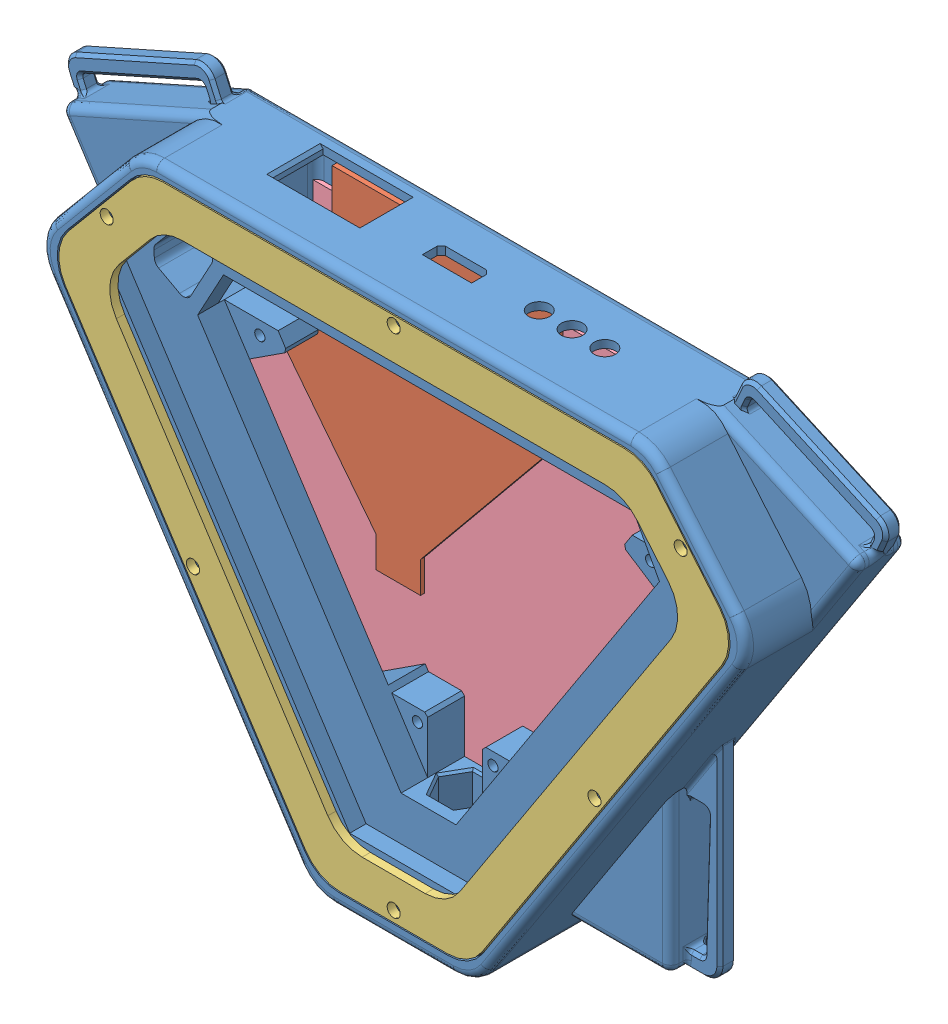
SolidWorks assembly Assemblage, configuration Défaut. Lengths in mm.
Overall size (200.07 141.58 28.14).
4 component instances, 4 part files, 8 mates.
Components (placement in the parent):
- plastron_avant-1: plastron_avant [Défaut] at (6.8106 -7.4855 171.5769) size (200.07 141.58 28.14)
- pcb_plastron_v1-1: pcb_plastron_v1 [Défaut] at (-15.0998 59.2795 174.5769) size (71.75 80.01 2)
- maintien_plexi-1: maintien_plexi [Défaut] at (-13.271 22.2938 197.5769) size (163.38 128.29 2)
- plexiglass-1: plexiglass [Défaut] at (-118.0737 -51.4237 174.5769) size (155.3 117.06 1)
Mates (geometry in assembly coordinates):
- Coaxiale1: concentric aligned: cylinder of plastron_avant-1 through (-15.2687 -31.0237 179.5769) axis (0 0 1) radius 1.25; cylinder of cache_batterie-1 through (-15.2687 -31.0237 184.5769) axis (0 0 1) radius 1.6
- Parallèle1: parallel anti-aligned: plane of plastron_avant-1 through (0.1011 -51.6091 191.0769) normal (0 1 0); plane of cache_batterie-1 through (-15.2687 -35.7237 187.0769) normal (0 -1 0)
- Coïncidente2: coincident anti-aligned: plane of plastron_avant-1 through (-15.2687 8.0998 184.5769) normal (0 0 1); plane of cache_batterie-1 through (-15.2687 -35.7237 184.5769) normal (0 0 -1)
- Coïncidente3: coincident anti-aligned: plane of plastron_avant-1 through (6.8106 -7.4855 174.5769) normal (0 0 1); plane of pcb_plastron_v1-1 through (-15.0998 59.2795 174.5769) normal (0 0 -1)
- Distance1: distance = 0.2 mm anti-aligned: plane of pcb_plastron_v1-1 through (24.1432 58.0095 176.5769) normal (0 1 0); plane of plastron_avant-1 through (6.8106 58.2095 171.5769) normal (0 -1 0)
- Coïncidente6: coincident anti-aligned: plane of plastron_avant-1 through (6.8106 -7.4855 197.5769) normal (0 0 1); plane of maintien_plexi-1 through (-13.271 22.2938 197.5769) normal (0 0 -1)
- Distance3: distance = 0.5 mm: line of plexiglass-1 through (-51.7258 51.7095 174.5769) axis (1 0 0); plane of plastron_avant-1 through (65.5801 52.2095 421.9629) normal (0 -1 0)
- Distance4: distance = 0.5 mm: line of plexiglass-1 through (-9.449 -65.3478 174.5769) axis (-0.545692 0.837986 0); plane of plastron_avant-1 through (-71.4625 28.9661 421.9629) normal (0.837986 0.545692 0)
